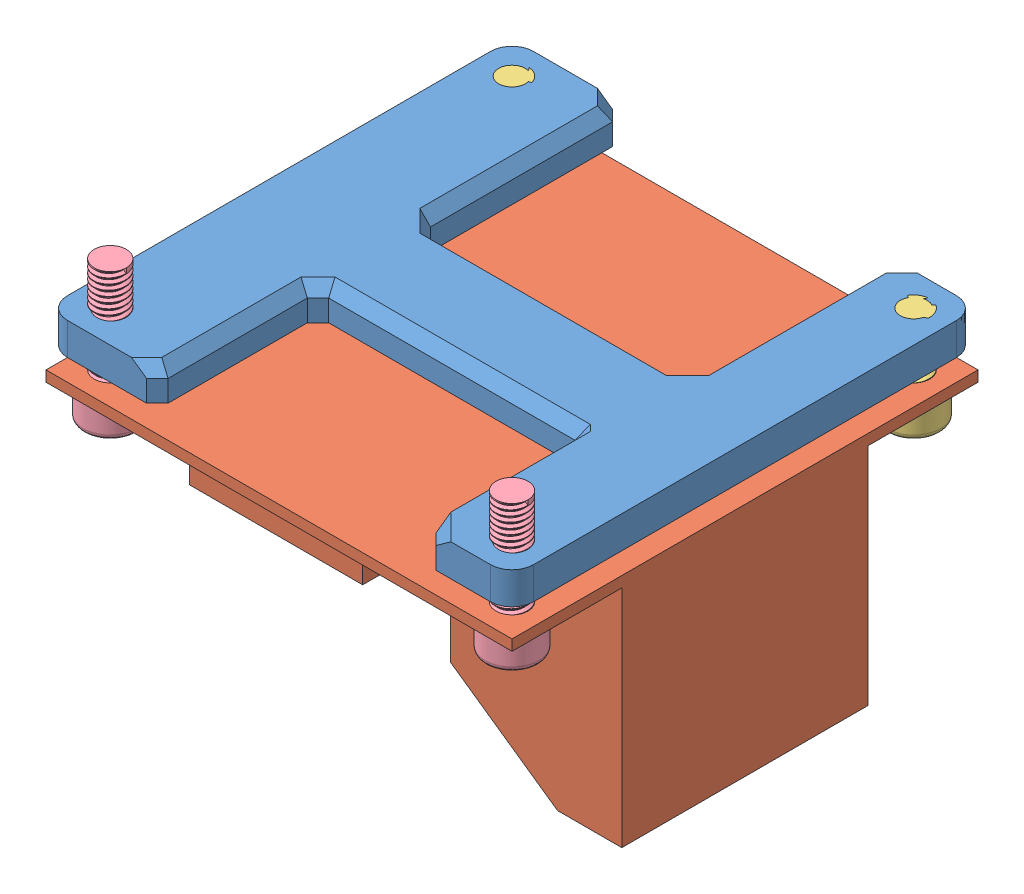
SolidWorks assembly carry, configuration Predeterminado. Lengths in mm.
Overall size (43.5 31 43.5).
6 component instances, 4 part files, 6 mates.
Components (placement in the parent):
- carrypuenteh-1: carrypuenteh [Predeterminado] at (-8.4342 -1.8235 42.8062) x (1 0 0) z (0 0 -1) size (43.5 3 43.5)
- l298-1: l298 [Predeterminado] at (-27.1842 -6.8235 24.0562) x (0 0 -1) z (-1 0 0) size (43.5 22 43.5)
- Tornillo M3x6-1: Tornillo M3x6 [Predeterminado] at (-45.9342 -1.8235 5.3062) x (1 0 0) z (0 -1 0) size (5 5 9)
- Tornillo M3x6-2: Tornillo M3x6 [Predeterminado] at (-8.4342 -1.8235 5.3062) x (1 0 0) z (0 -1 0) size (5 5 9)
- Tornillo M3x10_2-1: Tornillo M3x10_2 [Predeterminado] at (-45.9342 2.1765 42.8062) x (1 0 0) z (0 -1 0) size (5 5 13)
- Tornillo M3x10_2-2: Tornillo M3x10_2 [Predeterminado] at (-8.4342 2.1765 42.8062) x (1 0 0) z (0 -1 0) size (5 5 13)
Mates (geometry in assembly coordinates):
- Ancho1: width: plane of l298-1 through (-48.9342 -7.8235 2.3062) normal (0 0 -1); plane of l298-1 through (-48.9342 -7.8235 45.8062) normal (0 0 1); plane of carrypuenteh-1 through (-12.543 -4.8235 45.8062) normal (0 0 1); plane of carrypuenteh-1 through (-12.543 -4.8235 2.3062) normal (0 0 -1)
- Concéntrica1: concentric aligned: circle of carrypuenteh-1; circle of l298-1
- CentroDePerfil1: profile center anti-aligned: circle of Tornillo M3x6-1; circle of l298-1
- CentroDePerfil2: profile center anti-aligned: circle of Tornillo M3x6-2; circle of l298-1
- CentroDePerfil3: profile center anti-aligned: circle of Tornillo M3x10_2-1; circle of l298-1
- CentroDePerfil4: profile center anti-aligned: circle of Tornillo M3x10_2-2; circle of l298-1
